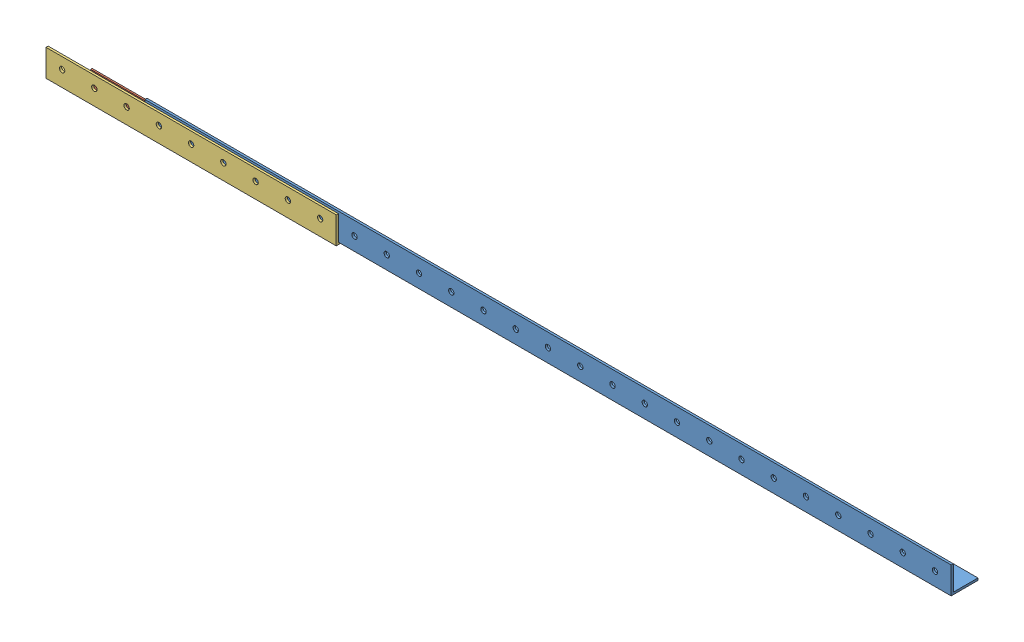
SolidWorks assembly Сборка1, configuration По умолчанию. Lengths in mm.
Overall size (1680 54 54).
3 component instances, 3 part files, 6 mates.
Components (placement in the parent):
- Ребро1500-1: Ребро1500 [По умолчанию] at origin size (1500 50 50)
- КреплениеГ1-1: КреплениеГ1 [По умолчанию] at (105 4 -4) x (0 1 0) z (0 0 1) size (40 210 40)
- Шаблон50-1: Шаблон50 [По умолчанию] at (-180 -4 4) size (540 50 50)
Mates (geometry in assembly coordinates):
- Концентричный1: concentric aligned: cylinder of Ребро1500-1 through (90 25 -50) axis (0 0 1) radius 5; cylinder of КреплениеГ1-1 through (90 25 -44) axis (0 0 1) radius 5
- Концентричный2: concentric aligned: cylinder of Ребро1500-1 through (30 25 -50) axis (0 0 1) radius 5; cylinder of КреплениеГ1-1 through (30 25 -44) axis (0 0 1) radius 5
- Концентричный3: concentric aligned: cylinder of Ребро1500-1 through (30 50 -25) axis (0 -1 0) radius 5; cylinder of КреплениеГ1-1 through (30 44 -25) axis (0 -1 0) radius 5
- Совпадение2: coincident anti-aligned: plane of Ребро1500-1 through (1500 0 0) normal (0 0 1); plane of Шаблон50-1 through (240 -4 0) normal (0 0 -1)
- Совпадение3: coincident anti-aligned: plane of Ребро1500-1 through (1500 0 0) normal (0 -1 0); plane of Шаблон50-1 through (240 0 4) normal (0 1 0)
- Концентричный4: concentric aligned: cylinder of Шаблон50-1 through (330 46 -25) axis (0 -1 0) radius 5; cylinder of Ребро1500-1 through (330 50 -25) axis (0 -1 0) radius 5
